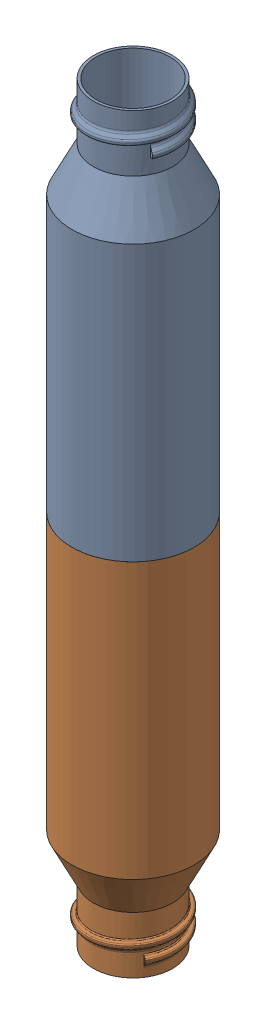
SolidWorks assembly iGem_core_V2, configuration Default. Lengths in mm.
Overall size (38.84 172 38.84).
2 component instances, 1 part files, 2 mates.
Components (placement in the parent):
- igem_core_half-1: igem_core_half [По умолчанию] at (26.3827 15.4617 50.1134) size (28 86 28)
- igem_core_half-2: igem_core_half [По умолчанию] at (52.0213 15.4617 57.8944) x (-0.831325 0 -0.555787) z (-0.555787 0 0.831325) size (28 86 28)
Mates (geometry in assembly coordinates):
- Совпадение1: coincident anti-aligned: plane of igem_core_v2.2-1 through (26.3827 15.4617 50.1134) normal (0 -1 0); plane of igem_core_v2.2-2 through (52.0213 15.4617 57.8944) normal (0 1 0)
- Совпадение2: coincident anti-aligned: circle of igem_core_v2.2-1; circle of igem_core_v2.2-2
